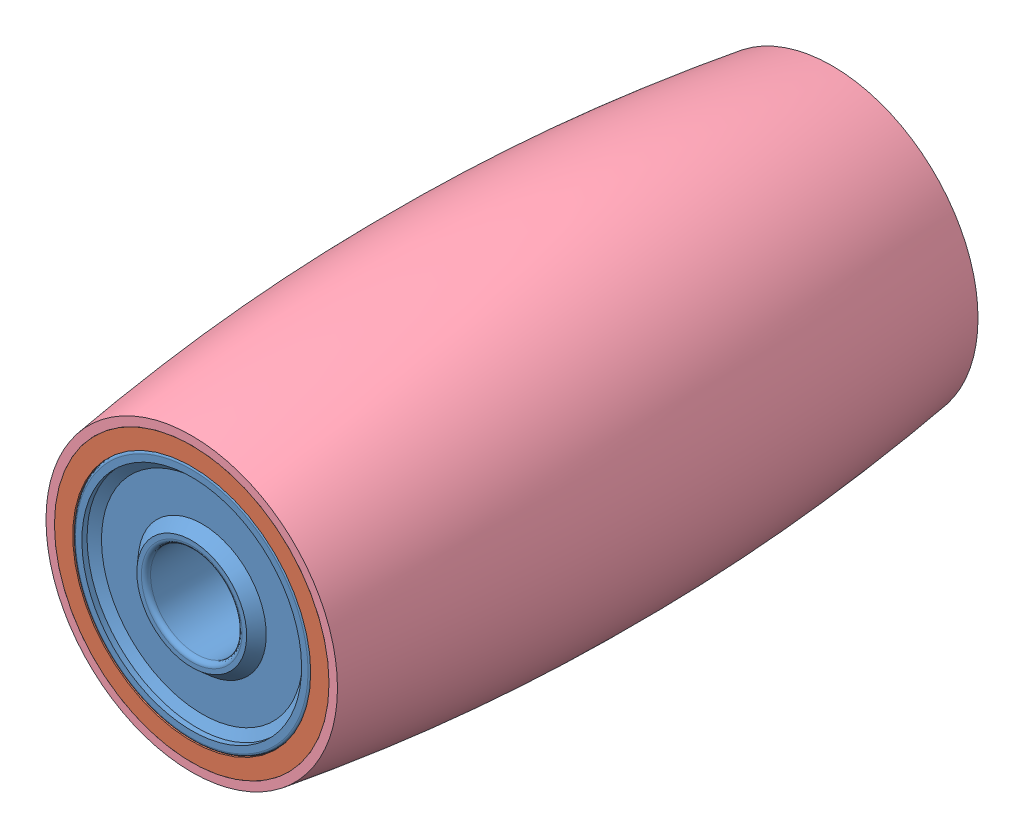
SolidWorks assembly ТП.SH21(К4).01.02.00 - Ролик диагональный, configuration 00. Lengths in mm.
Overall size (37 37 69.98).
6 component instances, 5 part files, 11 mates.
Components (placement in the parent):
- Боченок габарит-1: Боченок габарит [--] at origin size (37 37 91.92) (hidden)
- Подшипник 6100-1: Подшипник 6100 [--] at (0 0 30.99) x (0 0 1) z (0.161819 -0.986821 0) size (8 26 26)
- ТП.SH21(К4).01.02.01 - Ступица-1: ТП.SH21(К4).01.02.01 - Ступица [--] at origin size (30 30 69.98)
- ТП.SH21(К4).01.02.02 - Ось-1: ТП.SH21(К4).01.02.02 - Ось [--] at origin size (14 14 53.98)
- Подшипник 6100-2: Подшипник 6100 [--] at (0 0 -30.99) x (0 0 -1) z (-0.273874 0.961766 0) size (8 26 26)
- ТП.SH21(К4).01.02.03 - Покрышка-1: ТП.SH21(К4).01.02.03 - Покрышка [--] at origin size (37 37 69.98)
Mates (geometry in assembly coordinates):
- Совпадение1: coincident: line of Боченок габарит-1 through (0 0 45.9619) axis (0 0 -1); plane of assembly through (0 0 0) normal (0 1 0)
- Совпадение2: coincident: line of ? through (0 0 45.9619) axis (0 0 -1)
- Совпадение3: coincident: circle of Боченок габарит-1; plane of assembly through (0 0 0) normal (0 0 1)
- Совпадение4: coincident: plane of Боченок габарит-1 through (0 0 0) normal (0 1 0); plane of assembly through (0 0 0) normal (0 1 0)
- Концентричный1: concentric: line of Боченок габарит-1 through (0 0 45.9619) axis (0 0 -1); cylinder of Подшипник 6100-1 through (0 0 -969.01) axis (0 0 -1) radius 5
- Совпадение5: coincident: circle of Боченок габарит-1; plane of Подшипник 6100-1 through (-12.5326 -2.0551 34.99) normal (0 0 1)
- Совпадение6: coordinate: point of ?
- Совпадение7: coordinate: unknown of ?
- Совпадение8: coincident: plane of ТП.SH21(К4).01.02.01 - Ступица-1 through (12 0 -26.99) normal (0 0 -1); plane of Подшипник 6100-2 through (-12.0221 -3.4234 -26.99) normal (0 0 1)
- Концентричный2: concentric: cylinder of ТП.SH21(К4).01.02.02 - Ось-1 through (0 0 -26.99) axis (0 0 -1) radius 4.4; cylinder of Подшипник 6100-2 through (0 0 969.01) axis (0 0 1) radius 5
- Совпадение9: coordinate: unknown of ?
